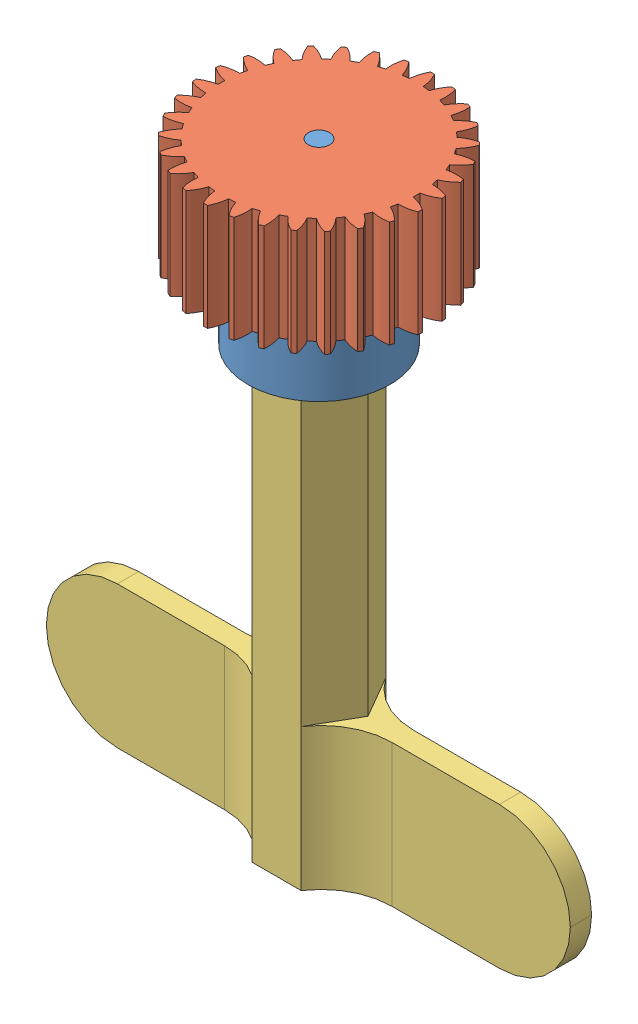
SolidWorks assembly key pinion, configuration Default. Lengths in mm.
Overall size (73.8 97 32).
3 component instances, 3 part files, 5 mates.
Components (placement in the parent):
- key block-1: key block [Default] at (4.1369 4.0548 19.5474) size (20 35 20)
- spur gear_am-1: spur gear_am [Metric - Spur gear 1M 30T 20PA 15FW ---S30N75H50L3N] at (4.1369 29.0548 19.5474) x (0 -1 0) z (0 0 1) size (15 31.88 32)
- key-1: key [Default] at (4.1369 12.0548 19.5474) x (-1 0 0) z (0 0 1) size (73.8 70 11.95)
Mates (geometry in assembly coordinates):
- Concentric1: concentric anti-aligned: cylinder of key block-1 through (4.1369 29.0548 19.5474) axis (0 -1 0) radius 1.5; cylinder of spur gear_am-1 through (4.1369 -20.9453 19.5474) axis (0 1 0) radius 1.5
- Coincident1: coincident anti-aligned: plane of key block-1 through (4.1369 14.0548 19.5474) normal (0 1 0); plane of spur gear_am-1 through (4.1369 14.0548 19.5474) normal (0 -1 0)
- Coincident3: coincident anti-aligned: line of key block-1 through (4.1369 14.0548 19.5474) axis (0 -1 0); line of key-1 through (4.1369 -29.9452 19.5474) axis (0 1 0)
- Coincident4: coincident anti-aligned: plane of key block-1 through (4.1369 12.0548 19.5474) normal (0 -1 0); plane of key-1 through (4.1369 12.0548 19.5474) normal (0 1 0)
- Parallel1: parallel anti-aligned: plane of key block-1 through (-2.8631 12.0548 19.5474) normal (0.866025 0 0.5); plane of key-1 through (-2.7631 -57.9452 19.5474) normal (-0.866025 0 -0.5)
